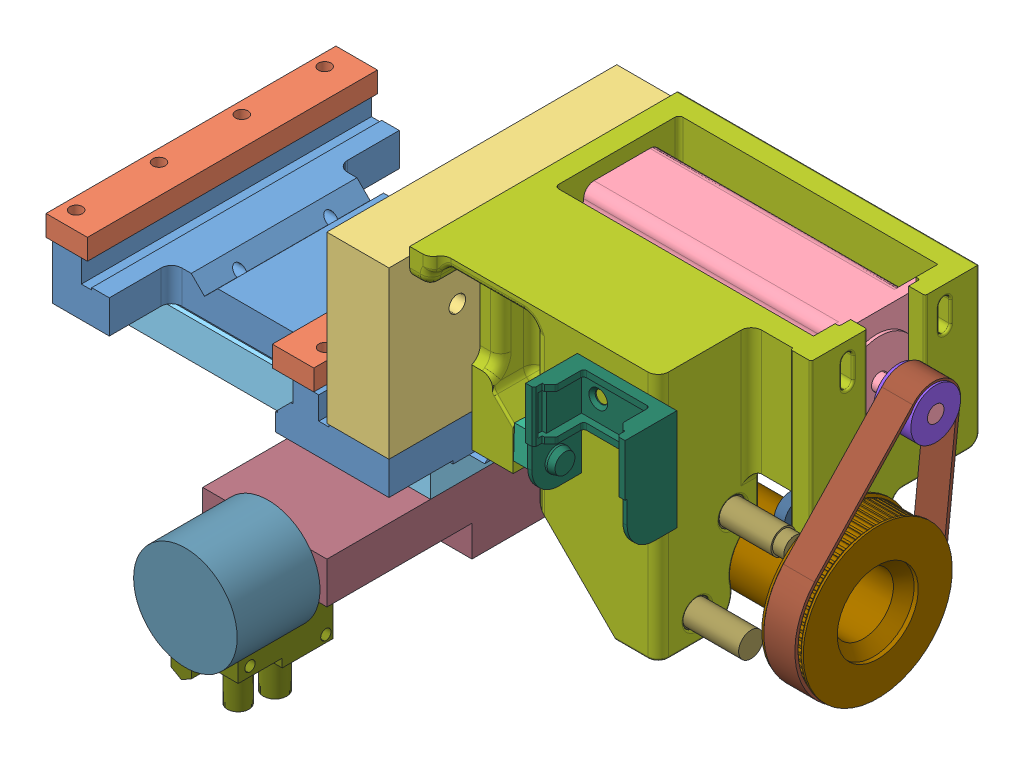
SolidWorks assembly carrete_assembly, configuration Default. Lengths in mm.
Overall size (354.72 209.2 212.13).
19 component instances, 16 part files, 45 mates.
Components (placement in the parent):
- carrete-1: carrete [Default] at (157.475 92.5899 64.1728) size (162.5 35 140)
- line-3: line [Default] at (25.5709 98.7659 204.1728) x (-1 0 0) z (0 0 -1) size (20 10 140)
- line-4: line [Default] at (114.8551 98.7659 64.1728) size (20 10 140)
- box_gear-1: box_gear [Default] at (148.0103 98.9539 109.3031) x (0 0 1) z (0 1 0) size (140 30 80)
- motor_57_123-1: motor_57_123 [Default] at (183.1516 144.591 106.437) x (0 -1 0) z (1 0 0) size (57 57 151.5)
- y_line-1: y_line [Default] at (162.435 87.2788 124.3662) x (0 0 -1) z (-1 0 0) size (80 18 180)
- round_extender-1: round_extender [Default] at (252.1516 82.9539 134.1728) x (0 -0.03118 -0.999514) z (-1 0 0) size (60 38.01 61)
- y_motor_holder-1: y_motor_holder [Default] at (171.1516 115.6271 129.7173) x (0 0 1) z (1 0 0) size (130.31 126 156)
- sleeve15-1: sleeve15 [Default] at (334.6516 149.4522 103.6728) x (0 -0.763132 -0.646242) z (-1 0 0) size (24 24 18)
- extend_gear-1: extend_gear [Default] at (252.1516 82.9539 134.1728) x (0 0.822418 -0.568884) z (1 0 0) size (75.4 75.4 85)
- bering-1: bering [Default] at (299.1516 104.148 119.1125) size (5 16 16)
- bering-2: bering [Default] at (299.1516 108.6218 138.3148) size (5 16 16)
- belt_15-1: belt_15 [Default] at (318.6516 149.4522 103.6728) x (0 -0.781721 0.623628) z (1 0 0) size (120.5 73 15)
- big_sensor-1: big_sensor [Default] at (311.9822 74.9539 170.1728) x (0 0.633345 0.77387) z (-1 0 0) size (19 19 60.5)
- big_sensor-2: big_sensor [Default] at (255.3735 108.5804 152.9424) x (0 0.959068 0.283176) z (1 0 0) size (19 19 60.5)
- lp-1: lp [Default] at (134.301 45.3199 95.3872) x (0 0 1) z (1 0 0) size (130 35 60)
- rl-1: rl [Default] at (134.0909 48.9318 265.3872) x (0 0 -1) z (1 0 0) size (40 50 50)
- in_element-1: in_element [Default] at (247.148 187.5375 190.4533) x (0 1 0) z (1 0 0) size (49 25 48)
- injector-1: injector [Default] at (102.535 47.7491 277.1328) x (0 0 1) z (1 0 0) size (75.8 59.7 24.9)
Mates (geometry in assembly coordinates):
- Coincident2: coincident anti-aligned: plane of carrete-1 through (8.6516 108.9539 204.1728) normal (0 1 0); plane of line-3 through (25.5709 108.9539 64.1728) normal (0 -1 0)
- Coincident4: coincident anti-aligned: plane of carrete-1 through (124.759 108.9539 204.1728) normal (0 1 0); plane of line-4 through (114.8551 108.9539 204.1728) normal (0 -1 0)
- Coincident5: coincident aligned: plane of carrete-1 through (157.475 92.5899 204.1728) normal (0 0 1); plane of line-4 through (114.8551 98.7659 204.1728) normal (0 0 1)
- Coincident6: coincident aligned: plane of carrete-1 through (157.475 92.5899 204.1728) normal (0 0 1); plane of line-3 through (25.5709 98.7659 204.1728) normal (0 0 1)
- Coincident7: coincident anti-aligned: plane of carrete-1 through (142.259 98.9539 204.1728) normal (0 1 0); plane of box_gear-1 through (148.0103 98.9539 109.3031) normal (0 -1 0)
- Coincident8: coincident aligned: plane of carrete-1 through (171.1516 98.9539 204.1728) normal (1 0 0); plane of box_gear-1 through (171.1516 178.9539 64.1728) normal (1 0 0)
- Coincident9: coincident aligned: plane of carrete-1 through (157.475 92.5899 64.1728) normal (0 0 -1); plane of box_gear-1 through (171.1516 178.9539 64.1728) normal (0 0 -1)
- Coincident11: distance = 2.5 mm anti-aligned: plane of carrete-1 through (8.6516 73.9539 110.4228) normal (0 0.707107 -0.707107); plane of y_line-1 through (-17.5651 73.4539 106.3872) normal (0 -0.707107 0.707107)
- Coincident15: coincident anti-aligned: plane of box_gear-1 through (171.1516 178.9539 64.1728) normal (1 0 0); plane of y_motor_holder-1 through (171.1516 115.6271 129.7173) normal (-1 0 0)
- Coincident16: coincident aligned: plane of carrete-1 through (171.1516 82.9539 204.1728) normal (0 -1 0); plane of y_motor_holder-1 through (181.1516 82.9539 64.1728) normal (0 -1 0)
- Coincident17: coincident aligned: plane of box_gear-1 through (171.1516 178.9539 64.1728) normal (0 0 -1); plane of y_motor_holder-1 through (181.1516 82.9539 64.1728) normal (0 0 -1)
- Coincident18: coincident anti-aligned: plane of motor_57_123-1 through (306.1516 144.591 106.437) normal (1 0 0); plane of y_motor_holder-1 through (306.1516 115.6271 129.7173) normal (-1 0 0)
- Coincident20: coincident anti-aligned: plane of round_extender-1 through (191.1516 82.9539 134.1728) normal (-1 0 0); plane of y_motor_holder-1 through (191.1516 115.6271 129.7173) normal (1 0 0)
- Concentric1: concentric anti-aligned: cylinder of motor_57_123-1 through (334.6516 149.4522 103.6728) axis (-1 0 0) radius 4; cylinder of sleeve15-1 through (316.6516 149.4522 103.6728) axis (1 0 0) radius 4
- Coincident21: coincident aligned: plane of motor_57_123-1 through (334.6516 149.4522 103.6728) normal (1 0 0); plane of sleeve15-1 through (334.6516 149.4522 103.6728) normal (1 0 0)
- Coincident22: coincident anti-aligned: plane of round_extender-1 through (252.1516 82.9539 134.1728) normal (1 0 0); plane of extend_gear-1 through (252.1516 82.9539 134.1728) normal (-1 0 0)
- Distance1: distance = 2 mm anti-aligned: plane of y_motor_holder-1 through (306.1516 115.6271 129.7173) normal (-1 0 0); plane of bering-1 through (304.1516 104.148 119.1125) normal (1 0 0)
- Concentric3: concentric anti-aligned: line of y_motor_holder-1 through (305.1516 104.148 119.1125) axis (1 0 0); cylinder of bering-1 through (304.1516 104.148 119.1125) axis (-1 0 0) radius 2.5
- Distance2: distance = 2 mm anti-aligned: plane of bering-2 through (304.1516 108.6218 138.3148) normal (1 0 0); plane of y_motor_holder-1 through (306.1516 115.6271 129.7173) normal (-1 0 0)
- Concentric4: concentric anti-aligned: cylinder of y_motor_holder-1 through (306.1516 108.6218 138.3148) axis (1 0 0) radius 3; cylinder of bering-2 through (304.1516 108.6218 138.3148) axis (-1 0 0) radius 2.5
- Distance4: distance = 11 mm aligned: plane of motor_57_123-1 through (306.1516 177.9522 75.1728) normal (0 0 -1); plane of y_motor_holder-1 through (181.1516 82.9539 64.1728) normal (0 0 -1)
- Concentric6: concentric anti-aligned: cylinder of sleeve15-1 through (316.6516 149.4522 103.6728) axis (1 0 0) radius 12; cylinder of belt_15-1 through (333.6516 149.4522 103.6728) axis (-1 0 0) radius 11.5
- Distance5: distance = 1 mm aligned: plane of belt_15-1 through (333.6516 149.4522 103.6728) normal (1 0 0); plane of sleeve15-1 through (334.6516 149.4522 103.6728) normal (1 0 0)
- Concentric7: concentric anti-aligned: cylinder of extend_gear-1 through (317.1516 82.9539 134.1728) axis (1 0 0) radius 37.2422; cylinder of belt_15-1 through (333.6516 82.9539 134.1728) axis (-1 0 0) radius 35
- Concentric9: concentric: cylinder of y_motor_holder-1 through (201.2253 74.0962 170.2994) axis (1 0 0) radius 4.75; cylinder of big_sensor-1 through (262.9392 74.0962 170.2994) axis (1 0 0) radius 6
- Concentric10: concentric anti-aligned: cylinder of y_motor_holder-1 through (266.1516 108.5804 152.9424) axis (1 0 0) radius 6.5; line of big_sensor-2 through (310.3735 108.5804 152.9424) axis (-1 0 0)
- Coincident23: coincident anti-aligned: plane of y_line-1 through (-17.565 63.4539 175.3872) normal (0 -1 0); plane of lp-1 through (162.435 63.4539 225.3872) normal (0 1 0)
- Coincident24: coincident aligned: plane of y_line-1 through (-17.565 63.4539 95.3872) normal (0 0 -1); plane of lp-1 through (134.301 45.3199 95.3872) normal (0 0 -1)
- Coincident26: coincident anti-aligned: plane of lp-1 through (134.301 45.3199 225.3872) normal (0 0 1); plane of rl-1 through (134.0909 48.9318 225.3872) normal (0 0 -1)
- Coincident27: coincident: plane of y_motor_holder-1 through (309.6769 81.4539 182.3557) normal (0 0 1); plane of in_element-1 through (247.8229 124.2543 182.3557) normal (0 0 -1)
- Parallel3: parallel anti-aligned: plane of y_motor_holder-1 through (171.1516 126.9539 129.7173) normal (0 -1 0); plane of in_element-1 through (251.148 173.758 214.1728) normal (0 1 0)
- Coincident28: coincident: cylinder of y_motor_holder-1 through (232.5716 133.1799 162.3557) axis (0 0 1) radius 3; circle of in_element-1
- Distance7: distance = 25 mm anti-aligned: plane of lp-1 through (102.435 43.4539 225.3872) normal (-1 0 0); plane of injector-1 through (127.435 47.7491 277.1328) normal (1 0 0)
- Distance6: distance = 30 mm aligned: plane of lp-1 through (162.435 63.4539 225.3872) normal (0 1 0); plane of injector-1 through (127.435 33.4539 187.4402) normal (0 1 0)
- Concentric11: concentric aligned: cylinder of y_motor_holder-1 through (266.1516 74.9539 170.1728) axis (1 0 0) radius 6.5; cylinder of big_sensor-1 through (256.9822 74.9539 170.1728) axis (1 0 0) radius 6
- Coincident30: coincident aligned: plane of y_line-1 through (162.435 87.2788 124.3662) normal (1 0 0); plane of lp-1 through (162.435 43.4539 225.3872) normal (1 0 0)
- Parallel4: parallel anti-aligned: plane of lp-1 through (102.435 43.4539 225.3872) normal (-1 0 0); plane of injector-1 through (127.435 47.7491 277.1328) normal (1 0 0)
- Concentric12: concentric aligned: cylinder of lp-1 through (134.0909 48.9318 25.3872) axis (0 0 1) radius 4.7672; cylinder of rl-1 through (134.0909 48.9318 225.3872) axis (0 0 1) radius 25
- Coincident31: coincident anti-aligned: plane of y_motor_holder-1 through (286.1516 62.9539 189.1728) normal (0 0 1); plane of in_element-1 through (251.148 148.758 189.1728) normal (0 0 -1)
- Концентричный1: concentric aligned: cylinder of carrete-1 through (-828.8484 82.9539 134.1728) axis (1 0 0) radius 7; cylinder of round_extender-1 through (152.1516 82.9539 134.1728) axis (1 0 0) radius 5
- Совпадение1: coincident anti-aligned: plane of carrete-1 through (8.6516 81.4539 117.9228) normal (0 -1 0); plane of y_line-1 through (-17.565 81.4539 175.3872) normal (0 1 0)
- Концентричный3: concentric anti-aligned: cylinder of round_extender-1 through (191.1516 82.9539 134.1728) axis (1 0 0) radius 18; line of extend_gear-1 through (315.1516 82.9539 134.1728) axis (-1 0 0)
- Параллельность1: parallel aligned: plane of motor_57_123-1 through (306.1516 177.9522 75.1728) normal (0 1 0); plane of y_motor_holder-1 through (181.1516 182.9539 64.1728) normal (0 1 0)
- Совпадение2: coincident anti-aligned: plane of round_extender-1 through (252.1516 82.9539 134.1728) normal (1 0 0); plane of metall_hendle-1 through (252.1516 82.9539 134.1728) normal (-1 0 0)
- Концентричный4: concentric aligned: cylinder of round_extender-1 through (191.1516 82.9539 134.1728) axis (1 0 0) radius 18; cylinder of metall_hendle-1 through (252.1516 82.9539 134.1728) axis (1 0 0) radius 17.5
